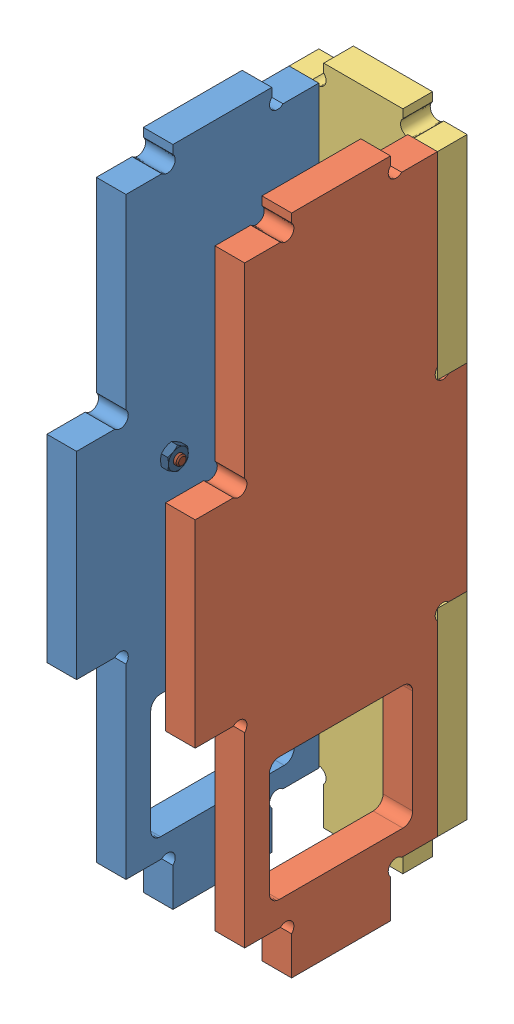
SolidWorks assembly pilier_gauche, configuration Défaut. Lengths in mm.
Overall size (44.26 134 55).
17 component instances, 11 part files, 26 mates.
Components (placement in the parent):
- pilier-cote-bouton-1: pilier-cote-bouton [Défaut] at (-45.8322 -68.3923 0) size (6 134 55)
- pilier-cote-2: pilier-cote [Défaut] at (-21.8322 -68.3923 0) size (6 134 55)
- pilier-devant-1: pilier-devant [Défaut] at (-45.8322 -68.3923 -55) size (30 134 6)
- vis-tf-m3x13-1: vis-tf-m3x13 [Défaut] at (-42.8322 41.6077 -55) x (-0.923728 -0.383049 0) z (0 0 -1) size (5.6 5.6 9)
- vis-tf-m3x13-2: vis-tf-m3x13 [Défaut] at (-18.8322 41.6077 -55) x (-0.923728 -0.383049 0) z (0 0 -1) size (5.6 5.6 9)
- entretoise-grove-1: entretoise-grove [Défaut] at (-47.8322 11.6077 -39) x (0 0 -1) z (1 0 0) size (4 4 2)
- entretoise-grove-2: entretoise-grove [Défaut] at (-47.8322 11.6077 -19) x (0 0 -1) z (1 0 0) size (4 4 2)
- Grove button-1: Grove button [Défaut] at (-46.5375 13.6873 -29) x (0 -1 0) z (0 0 -1) size (20 11.6 23.6)
  - PCB grove 20x20-1: PCB grove 20x20 [Défaut] at (2.0795 1.2947 0) size (20 1.6 23.6)
  - 603 resistor 102-1: 603 resistor 102 [Default] at (2.0895 2.8947 -6.319) x (0 0 1) z (-1 0 0) size (2.36 0.62 1.03)
  - tactileswitch-CMS-1: tactileswitch-CMS [Default] at (-2.4169 2.8947 0.0035) x (0 0 1) z (-1 0 0) size (8.41 4.95 6.01)
  - Connecteur Grove (droit CMS)-1: Connecteur Grove (droit CMS) [Défaut] at (5.0795 2.8947 0) x (-1 0 0) z (0 1 0) size (6.5 14 10)
  - 603 resistor 102-2: 603 resistor 102 [Default] at (3.5895 2.8947 -6.319) x (0 0 1) z (-1 0 0) size (2.36 0.62 1.03)
- ecrou-h-1: ecrou-h [6007 HU M2] at (-38.2322 11.6077 -39) x (0 -0.866025 0.5) z (0 0.5 0.866025) size (4 1.6 4.62)
- ecrou-h-2: ecrou-h [6007 HU M2] at (-38.2322 11.6077 -19) x (0 -0.866025 0.5) z (0 0.5 0.866025) size (4 1.6 4.62)
- vis-chc-1: vis-chc [Vis CHC M2x12] at (-49.4322 11.6077 -19) x (0 0.931711 0.363201) z (0 -0.363201 0.931711) size (3.8 14 3.8)
- vis-chc-2: vis-chc [Vis CHC M2x12] at (-49.4322 11.6077 -39) x (0 0.992378 -0.123233) z (0 0.123233 0.992378) size (3.8 14 3.8)
Mates (geometry in assembly coordinates):
- Coïncidente1: coincident aligned: plane of pilier-cote-bouton-1 through (-39.8322 61.6077 -41.7627) normal (0 1 0); plane of pilier-devant-1 through (-41.0949 61.6077 -49) normal (0 1 0)
- Coïncidente2: coincident aligned: plane of pilier-cote-2 through (-15.8322 61.6077 -41.7627) normal (0 1 0); plane of pilier-devant-1 through (-20.5694 61.6077 -49) normal (0 1 0)
- Coïncidente3: coincident aligned: plane of pilier-cote-bouton-1 through (-45.8322 -19.5236 -50.1314) normal (-1 0 0); plane of pilier-devant-1 through (-45.8322 21.6077 -49) normal (-1 0 0)
- Coïncidente4: coincident aligned: plane of pilier-cote-bouton-1 through (-39.8322 21.6077 -55) normal (0 0 -1); plane of pilier-devant-1 through (-21.7008 -59.5236 -55) normal (0 0 -1)
- Coïncidente5: coincident aligned: plane of pilier-cote-2 through (-15.8322 21.6077 -55) normal (0 0 -1); plane of pilier-devant-1 through (-21.7008 -59.5236 -55) normal (0 0 -1)
- Coïncidente6: coincident aligned: plane of pilier-cote-2 through (-15.8322 -19.5236 -50.1314) normal (1 0 0); plane of pilier-devant-1 through (-15.8322 21.6077 -49) normal (1 0 0)
- Coïncidente7: coincident aligned: line of pilier-devant-1 through (-42.8322 41.6077 -49) axis (0 0 -1); line of VIS TF 3 X 13-1 through (-42.8322 41.6077 -48.5115) axis (0 0 -1)
- Coïncidente8: coincident aligned: plane of pilier-devant-1 through (-21.7008 -59.5236 -55) normal (0 0 -1); circle of VIS TF 3 X 13-1
- Coïncidente10: coincident aligned: line of pilier-devant-1 through (-18.8322 41.6077 -49) axis (0 0 -1); line of VIS TF 3 X 13-2 through (-18.8322 41.6077 -48.5115) axis (0 0 -1)
- Coïncidente11: coincident aligned: plane of pilier-devant-1 through (-21.7008 -59.5236 -55) normal (0 0 -1); circle of VIS TF 3 X 13-2
- Coaxiale1: concentric anti-aligned: cylinder of Grove button-1/PCB grove 20x20-1 through (-49.4322 11.6077 -39) axis (1 0 0) radius 1.1; cylinder of entretoise-grove-1 through (-45.8322 11.6077 -39) axis (-1 0 0) radius 1.2
- Coïncidente14: coincident anti-aligned: plane of Grove button-1/PCB grove 20x20-1 through (-47.8322 11.6077 -29) normal (1 0 0); plane of entretoise-grove-1 through (-47.8322 11.6077 -39) normal (-1 0 0)
- Coaxiale2: concentric anti-aligned: cylinder of Grove button-1/PCB grove 20x20-1 through (-49.4322 11.6077 -19) axis (1 0 0) radius 1.1; cylinder of entretoise-grove-2 through (-45.8322 11.6077 -19) axis (-1 0 0) radius 1.2
- Coïncidente15: coincident anti-aligned: plane of Grove button-1/PCB grove 20x20-1 through (-47.8322 11.6077 -29) normal (1 0 0); plane of entretoise-grove-2 through (-47.8322 11.6077 -19) normal (-1 0 0)
- Coïncidente16: coincident anti-aligned: plane of pilier-cote-bouton-1 through (-45.8322 -19.5236 -50.1314) normal (-1 0 0); plane of entretoise-grove-2 through (-45.8322 11.6077 -19) normal (1 0 0)
- Coaxiale3: concentric aligned: cylinder of pilier-cote-bouton-1 through (-39.8322 11.6077 -39) axis (-1 0 0) radius 1; cylinder of entretoise-grove-1 through (-45.8322 11.6077 -39) axis (-1 0 0) radius 1.2
- Coaxiale4: concentric aligned: cylinder of pilier-cote-bouton-1 through (-39.8322 11.6077 -19) axis (-1 0 0) radius 1; cylinder of entretoise-grove-2 through (-45.8322 11.6077 -19) axis (-1 0 0) radius 1.2
- Coaxiale5: concentric anti-aligned: cylinder of Grove button-1/PCB grove 20x20-1 through (-49.4322 11.6077 -39) axis (1 0 0) radius 1.1; cylinder of vis-chc-2 through (-37.4322 11.6077 -39) axis (-1 0 0) radius 1
- Coaxiale6: concentric anti-aligned: line of Grove button-1/PCB grove 20x20-1 through (-49.4322 11.6077 -19) axis (1 0 0); cylinder of vis-chc-1 through (-37.4322 11.6077 -19) axis (-1 0 0) radius 1
- Coïncidente19: coincident anti-aligned: plane of Grove button-1/PCB grove 20x20-1 through (-49.4322 11.6077 -29) normal (-1 0 0); plane of vis-chc-1 through (-49.4322 11.6077 -19) normal (1 0 0)
- Coaxiale7: concentric anti-aligned: cylinder of ecrou-h-1 through (-39.8322 11.6077 -39) axis (1 0 0) radius 0.7835; cylinder of vis-chc-2 through (-37.4322 11.6077 -39) axis (-1 0 0) radius 1
- Coïncidente20: coincident anti-aligned: plane of pilier-cote-bouton-1 through (-39.8322 -19.5236 -50.1314) normal (1 0 0); plane of ecrou-h-1 through (-39.8322 9.2983 -39) normal (-1 0 0)
- Parallèle2: parallel anti-aligned: plane of pilier-devant-1 through (-21.7008 -59.5236 -49) normal (0 0 1); plane of ecrou-h-1 through (-39.8322 10.453 -41) normal (0 0 -1)
- Coaxiale8: concentric anti-aligned: cylinder of ecrou-h-2 through (-39.8322 11.6077 -19) axis (1 0 0) radius 0.7835; cylinder of vis-chc-1 through (-37.4322 11.6077 -19) axis (-1 0 0) radius 1
- Coïncidente22: coincident anti-aligned: plane of pilier-cote-bouton-1 through (-39.8322 -19.5236 -50.1314) normal (1 0 0); plane of ecrou-h-2 through (-39.8322 9.2983 -19) normal (-1 0 0)
- Parallèle3: parallel anti-aligned: plane of pilier-devant-1 through (-21.7008 -59.5236 -49) normal (0 0 1); plane of ecrou-h-2 through (-39.8322 10.453 -21) normal (0 0 -1)
